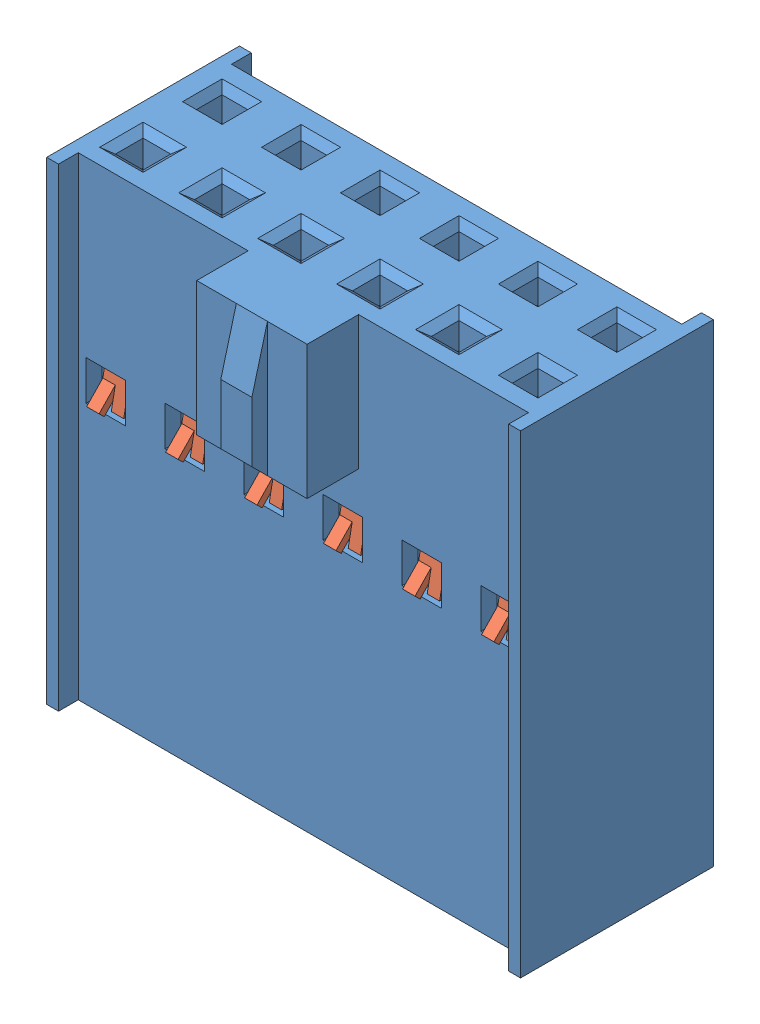
SolidWorks assembly PCB Header Connector 6x2, configuration Default. Lengths in mm.
Overall size (15.24 15.24 7.72).
13 component instances, 2 part files, 8 mates.
Components (placement in the parent):
- PCB Header Female Molex 6x2 Housing-1: PCB Header Female Molex 6x2 Housing [Default] at origin size (15.24 15.24 7.72)
- PCB Header Female 90119 Series Molex Connector - Gold 26-28 AWG (Mono)-2: PCB Header Female 90119 Series Molex Connector - Gold 26-28 AWG (Mono) [Défaut] at (-6.35 6.2508 0.635) size (2 13.3 2.06)
- PCB Header Female 90119 Series Molex Connector - Gold 26-28 AWG (Mono)-5: PCB Header Female 90119 Series Molex Connector - Gold 26-28 AWG (Mono) [Défaut] at (-3.81 6.2508 0.635) size (2 13.3 2.06)
- PCB Header Female 90119 Series Molex Connector - Gold 26-28 AWG (Mono)-7: PCB Header Female 90119 Series Molex Connector - Gold 26-28 AWG (Mono) [Défaut] at (-1.27 6.2508 0.635) size (2 13.3 2.06)
- PCB Header Female 90119 Series Molex Connector - Gold 26-28 AWG (Mono)-9: PCB Header Female 90119 Series Molex Connector - Gold 26-28 AWG (Mono) [Défaut] at (1.27 6.2508 0.635) size (2 13.3 2.06)
- PCB Header Female 90119 Series Molex Connector - Gold 26-28 AWG (Mono)-11: PCB Header Female 90119 Series Molex Connector - Gold 26-28 AWG (Mono) [Défaut] at (3.81 6.2508 0.635) size (2 13.3 2.06)
- PCB Header Female 90119 Series Molex Connector - Gold 26-28 AWG (Mono)-13: PCB Header Female 90119 Series Molex Connector - Gold 26-28 AWG (Mono) [Défaut] at (6.35 6.2508 0.635) size (2 13.3 2.06)
- PCB Header Female 90119 Series Molex Connector - Gold 26-28 AWG (Mono)-16: PCB Header Female 90119 Series Molex Connector - Gold 26-28 AWG (Mono) [Défaut] at (-6.35 6.2508 -0.635) x (-1 0 0) z (0 0 -1) size (2 13.3 2.06)
- PCB Header Female 90119 Series Molex Connector - Gold 26-28 AWG (Mono)-17: PCB Header Female 90119 Series Molex Connector - Gold 26-28 AWG (Mono) [Défaut] at (-3.81 6.2508 -0.635) x (-1 0 0) z (0 0 -1) size (2 13.3 2.06)
- PCB Header Female 90119 Series Molex Connector - Gold 26-28 AWG (Mono)-18: PCB Header Female 90119 Series Molex Connector - Gold 26-28 AWG (Mono) [Défaut] at (-1.27 6.2508 -0.635) x (-1 0 0) z (0 0 -1) size (2 13.3 2.06)
- PCB Header Female 90119 Series Molex Connector - Gold 26-28 AWG (Mono)-19: PCB Header Female 90119 Series Molex Connector - Gold 26-28 AWG (Mono) [Défaut] at (1.27 6.2508 -0.635) x (-1 0 0) z (0 0 -1) size (2 13.3 2.06)
- PCB Header Female 90119 Series Molex Connector - Gold 26-28 AWG (Mono)-20: PCB Header Female 90119 Series Molex Connector - Gold 26-28 AWG (Mono) [Défaut] at (3.81 6.2508 -0.635) x (-1 0 0) z (0 0 -1) size (2 13.3 2.06)
- PCB Header Female 90119 Series Molex Connector - Gold 26-28 AWG (Mono)-21: PCB Header Female 90119 Series Molex Connector - Gold 26-28 AWG (Mono) [Défaut] at (6.35 6.2508 -0.635) x (-1 0 0) z (0 0 -1) size (2 13.3 2.06)
Mates (geometry in assembly coordinates):
- Coincident41: coincident anti-aligned: plane of PCB Header Female Molex 6x2 Housing-1 through (-6.7945 6.4008 0.8255) normal (0 -1 0); plane of PCB Header Female 90119 Series Molex Connector - Gold 26-28 AWG (Mono)-2 through (-6.75 6.4008 0.635) normal (0 1 0)
- Coincident51: coincident anti-aligned: plane of PCB Header Female Molex 6x2 Housing-1 through (-6.985 0 0) normal (1 0 0); plane of PCB Header Female 90119 Series Molex Connector - Gold 26-28 AWG (Mono)-2 through (-6.985 6.2508 0.935) normal (-1 0 0)
- Coincident61: coincident anti-aligned: plane of PCB Header Female Molex 6x2 Housing-1 through (-5.9055 6.5913 0.635) normal (0 0 1); plane of PCB Header Female 90119 Series Molex Connector - Gold 26-28 AWG (Mono)-2 through (-5.915 6.2508 0.635) normal (0 0 -1)
- Width1: width aligned: plane of PCB Header Female Molex 6x2 Housing-1 through (-6.985 0 0) normal (1 0 0); plane of PCB Header Female Molex 6x2 Housing-1 through (-5.715 0 0) normal (-1 0 0); plane of PCB Header Female 90119 Series Molex Connector - Gold 26-28 AWG (Mono)-2 through (-6.885 6.2508 1.795) normal (1 0 0); plane of PCB Header Female 90119 Series Molex Connector - Gold 26-28 AWG (Mono)-2 through (-5.815 6.2508 0.935) normal (-1 0 0)
- Coincident101: coincident anti-aligned: plane of PCB Header Female Molex 6x2 Housing-1 through (-6.7945 6.4008 -1.905) normal (0 -1 0); plane of PCB Header Female 90119 Series Molex Connector - Gold 26-28 AWG (Mono)-16 through (-5.95 6.4008 -0.635) normal (0 1 0)
- Parallel11: parallel anti-aligned: plane of PCB Header Female Molex 6x2 Housing-1 through (-5.715 0 0) normal (-1 0 0); plane of PCB Header Female 90119 Series Molex Connector - Gold 26-28 AWG (Mono)-16 through (-5.615 6.2508 -0.935) normal (1 0 0)
- Coincident111: coincident anti-aligned: plane of PCB Header Female Molex 6x2 Housing-1 through (-5.9055 -7.62 -0.635) normal (0 0 -1); plane of PCB Header Female 90119 Series Molex Connector - Gold 26-28 AWG (Mono)-16 through (-6.785 6.2508 -0.635) normal (0 0 1)
- Width2: width aligned: plane of PCB Header Female Molex 6x2 Housing-1 through (-5.715 0 0) normal (-1 0 0); plane of PCB Header Female Molex 6x2 Housing-1 through (-6.985 0 0) normal (1 0 0); plane of PCB Header Female 90119 Series Molex Connector - Gold 26-28 AWG (Mono)-16 through (-7.085 6.2508 -1.795) normal (-1 0 0); plane of PCB Header Female 90119 Series Molex Connector - Gold 26-28 AWG (Mono)-16 through (-5.615 6.2508 -0.935) normal (1 0 0)
